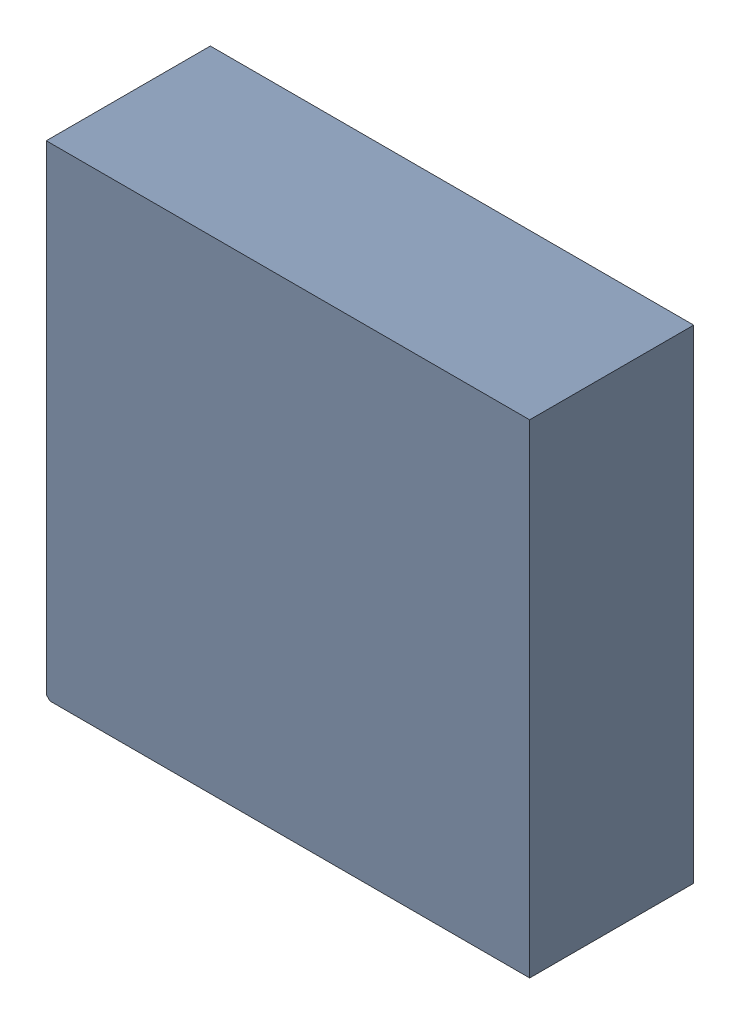
SolidWorks assembly U27, configuration ﾃﾞﾌｫﾙﾄ. Lengths in mm.
Overall size (3.3 3.3 1.12).
2 component instances, 1 part files, 0 mates.
Components (placement in the parent):
- 689262736-1: 689262736 [ﾃﾞﾌｫﾙﾄ] at (37 67 0) size (3.3 3.3 1.12)
  - Extruded_42-1: Extruded_42 [ﾃﾞﾌｫﾙﾄ] at origin size (3.3 3.3 1.12)
